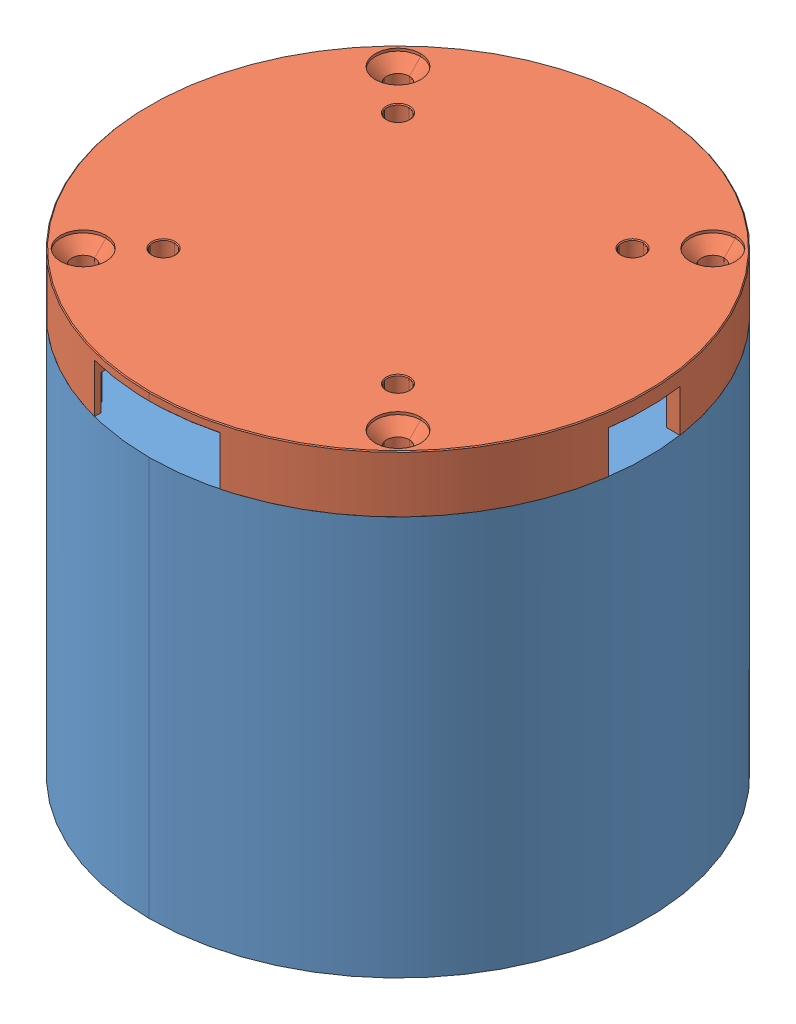
SolidWorks assembly DM 4340 电机 3D-231108, configuration 默认. Lengths in mm.
Overall size (57 53.25 57).
3 component instances, 2 part files, 0 mates.
Components (placement in the parent):
- DM 4340 电机 3D-231108.STEP-1: DM 4340 电机 3D-231108.STEP [默认] at origin size (57 53.25 57)
  - DM 4340 3D.STEP-1: DM 4340 3D.STEP [默认] at origin size (57 46.75 57)
  - 4310 ________________ Ver.B.STEP-1: 4310 ________________ Ver.B.STEP [默认] at (0 53.25 0) x (-1 0 0) z (0 0 1) size (57 6.5 57)
